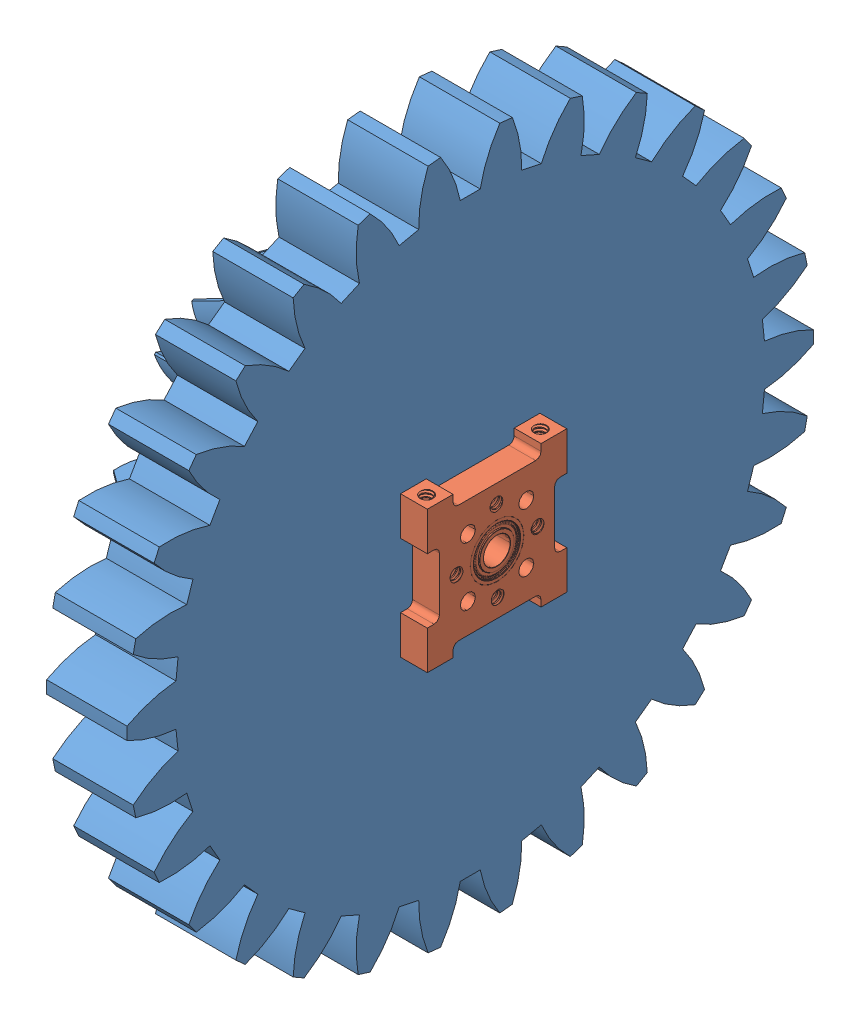
SolidWorks assembly ARMUS-REV2-300, configuration Default. Lengths in mm.
Overall size (57.21 161.95 162.56).
3 component instances, 2 part files, 7 mates.
Components (placement in the parent):
- ARMUS-REV2-100-1: ARMUS-REV2-100 [Default] at origin size (50.86 161.95 162.56)
- Bore Side Tapped Pillow Block 1.25-1: Bore Side Tapped Pillow Block 1.25 [Default] at (-39.4159 7.6184 -28.3917) x (0 -1 0) z (0 0 1) size (33.54 6.35 33.02)
- Bore Side Tapped Pillow Block 1.25-2: Bore Side Tapped Pillow Block 1.25 [Default] at (4.8346 7.6184 -28.3917) x (0 -1 0) z (0 0 1) size (33.54 6.35 33.02)
Mates (geometry in assembly coordinates):
- Coincident1: coordinate: point of ARMUS-REV2-100-1
- Concentric1: concentric anti-aligned: cylinder of ARMUS-REV2-100-1 through (-86.1279 0 0) axis (1 0 0) radius 6.35; cylinder of Bore Side Tapped Pillow Block 1.25-1 through (-18.8631 0 0) axis (-1 0 0) radius 3.175
- Parallel1: parallel aligned: plane of ARMUS-REV2-100-1 through (0 0 0) normal (0 1 0); plane of Bore Side Tapped Pillow Block 1.25-1 through (-18.8504 13.9065 -10.414) normal (0 1 0)
- Coincident3: coincident anti-aligned: plane of ARMUS-REV2-100-1 through (-18.8504 0 0) normal (-1 0 0); plane of Bore Side Tapped Pillow Block 1.25-1 through (-18.8504 0 0) normal (1 0 0)
- Concentric2: concentric anti-aligned: cylinder of ARMUS-REV2-100-1 through (-86.1279 0 0) axis (1 0 0) radius 6.35; cylinder of Bore Side Tapped Pillow Block 1.25-2 through (25.3873 0 0) axis (-1 0 0) radius 3.175
- Parallel2: parallel aligned: plane of Bore Side Tapped Pillow Block 1.25-1 through (-18.8504 13.9065 -10.414) normal (0 1 0); plane of Bore Side Tapped Pillow Block 1.25-2 through (25.4 13.9065 -10.414) normal (0 1 0)
- Coincident4: coincident anti-aligned: plane of ARMUS-REV2-100-1 through (19.05 0 0) normal (1 0 0); plane of Bore Side Tapped Pillow Block 1.25-2 through (19.05 0 0) normal (-1 0 0)
